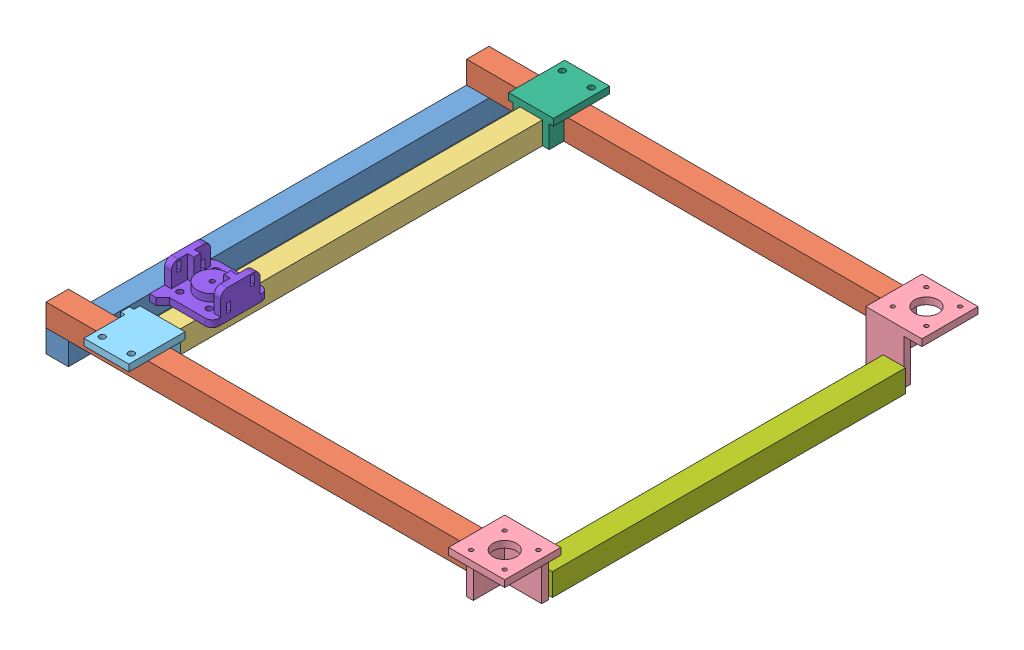
SolidWorks assembly Rails, configuration Domyślna. Lengths in mm.
Overall size (425 66 429).
10 component instances, 8 part files, 28 mates.
Components (placement in the parent):
- Rail_395-1: Rail_395 [Domyślna] at (147.1484 163.3689 533.8319) size (20 20 395)
- Rail_345-1: Rail_345 [Domyślna] at (147.1484 183.3689 513.8319) x (0 0 1) z (-1 0 0) size (20 20 375)
- Rail_345-2: Rail_345 [Domyślna] at (147.1484 183.3689 138.8319) x (0 0 1) z (-1 0 0) size (20 20 375)
- Rail_350-1: Rail_350 [Domyślna] at (207.86 183.3689 511.3319) size (20 20 350)
- Support_moteur-1: Support_moteur [Domyślna] at (572.1484 209.3689 549.8319) x (-1 0 0) z (0 -1 0) size (50 50 46)
- Support_moteur-2: Support_moteur [Domyślna] at (572.1484 209.3689 127.8319) x (0 0 1) z (0 -1 0) size (50 50 46)
- Support_milieu-1: Support_milieu [Domyślna] at (198.06 209.3689 500.8319) x (1 0 0) z (0 -1 0) size (44 50 26)
- Support_milieu_B-1: Support_milieu_B [Domyślna] at (237.66 209.3689 171.8319) x (-1 0 0) z (0 -1 0) size (40 50 26)
- Rail_315-1: Rail_315 [Domyślna] at (541.1484 163.3689 496.3319) size (20 20 315)
- Support_aimant-1: Support_aimant [Domyślna] at (192.86 209.3689 481.256) x (1 0 0) z (0 1 0) size (50 56 26)
Mates (geometry in assembly coordinates):
- Wspólnie1: coincident anti-aligned: plane of Rail_395-1 through (147.1484 183.3689 138.8319) normal (0 1 0); plane of Rail_345-1 through (522.1484 183.3689 513.8319) normal (0 -1 0)
- Wspólnie2: coincident aligned: plane of Rail_395-1 through (147.1484 163.3689 533.8319) normal (0 0 1); plane of Rail_345-1 through (522.1484 183.3689 533.8319) normal (0 0 1)
- Wspólnie3: coincident aligned: plane of Rail_395-1 through (147.1484 163.3689 138.8319) normal (-1 0 0); plane of Rail_345-1 through (147.1484 183.3689 513.8319) normal (-1 0 0)
- Wspólnie4: coincident anti-aligned: plane of Rail_395-1 through (147.1484 183.3689 138.8319) normal (0 1 0); plane of Rail_345-2 through (522.1484 183.3689 138.8319) normal (0 -1 0)
- Wspólnie5: coincident aligned: plane of Rail_395-1 through (147.1484 163.3689 138.8319) normal (0 0 -1); plane of Rail_345-2 through (522.1484 183.3689 138.8319) normal (0 0 -1)
- Wspólnie6: coincident aligned: plane of Rail_395-1 through (147.1484 163.3689 138.8319) normal (-1 0 0); plane of Rail_345-2 through (147.1484 183.3689 138.8319) normal (-1 0 0)
- Wspólnie8: coincident aligned: plane of Rail_345-1 through (522.1484 203.3689 513.8319) normal (0 1 0); plane of Rail_350-1 through (207.86 203.3689 161.3319) normal (0 1 0)
- Odległość1: distance = 2.5 mm anti-aligned: plane of Rail_350-1 through (207.86 183.3689 161.3319) normal (0 0 -1); plane of Rail_345-2 through (522.1484 183.3689 158.8319) normal (0 0 1)
- Wspólnie11: coincident anti-aligned: plane of Rail_345-1 through (522.1484 183.3689 513.8319) normal (1 0 0); plane of Support_moteur-1 through (522.1484 203.3689 549.8319) normal (-1 0 0)
- Wspólnie12: coincident anti-aligned: plane of Rail_345-2 through (522.1484 183.3689 138.8319) normal (1 0 0); plane of Support_moteur-2 through (522.1484 203.3689 127.8319) normal (-1 0 0)
- Równolegle1: parallel aligned: plane of Rail_345-2 through (522.1484 203.3689 138.8319) normal (0 1 0); plane of Support_moteur-2 through (572.1484 209.3689 127.8319) normal (0 1 0)
- Wspólnie14: coincident: plane of Rail_395-1 through (147.1484 163.3689 138.8319) normal (0 -1 0); line of Support_moteur-2 through (522.1484 163.3689 177.8319) axis (0 0 -1)
- Wspólnie15: coincident: plane of Rail_395-1 through (147.1484 163.3689 138.8319) normal (0 -1 0); line of Support_moteur-1 through (522.1484 163.3689 533.8319) axis (0 0 -1)
- Wspólnie16: coincident: plane of Rail_345-1 through (522.1484 183.3689 533.8319) normal (0 0 1); line of Support_moteur-1 through (522.1484 163.3689 533.8319) axis (0 1 0)
- Wspólnie17: coincident aligned: plane of Rail_345-2 through (522.1484 183.3689 138.8319) normal (0 0 -1); plane of Support_moteur-2 through (572.1484 163.3689 138.8319) normal (0 0 -1)
- Wspólnie18: coincident anti-aligned: plane of Rail_350-1 through (207.86 203.3689 161.3319) normal (0 1 0); plane of Support_milieu-1 through (198.06 203.3689 500.8319) normal (0 -1 0)
- Wspólnie19: coincident anti-aligned: plane of Rail_345-1 through (522.1484 183.3689 513.8319) normal (0 0 -1); plane of Support_milieu-1 through (234.26 183.3689 513.8319) normal (0 0 1)
- Wspólnie20: coincident anti-aligned: plane of Rail_350-1 through (207.86 183.3689 161.3319) normal (-1 0 0); plane of Support_milieu-1 through (207.86 183.3689 500.8319) normal (1 0 0)
- Wspólnie21: coincident anti-aligned: plane of Rail_350-1 through (207.86 203.3689 161.3319) normal (0 1 0); plane of Support_milieu_B-1 through (237.66 203.3689 171.8319) normal (0 -1 0)
- Wspólnie23: coincident anti-aligned: plane of Rail_345-2 through (522.1484 183.3689 158.8319) normal (0 0 1); plane of Support_milieu_B-1 through (233.86 183.3689 158.8319) normal (0 0 -1)
- Wspólnie24: coincident anti-aligned: plane of Rail_350-1 through (227.86 183.3689 161.3319) normal (1 0 0); plane of Support_milieu_B-1 through (227.86 183.3689 171.8319) normal (-1 0 0)
- Wspólnie29: coincident: line of Support_moteur-1 through (561.1484 163.3689 499.8319) axis (0 1 0); plane of Rail_315-1 through (561.1484 163.3689 181.3319) normal (1 0 0)
- Wspólnie30: coincident: line of Support_moteur-1 through (522.1484 163.3689 499.8319) axis (1 0 0); plane of Rail_315-1 through (541.1484 163.3689 181.3319) normal (0 -1 0)
- Wspólnie31: coincident aligned: plane of Support_moteur-1 through (561.1484 163.3689 549.8319) normal (1 0 0); plane of Rail_315-1 through (561.1484 163.3689 181.3319) normal (1 0 0)
- Wspólnie32: coincident aligned: plane of Support_moteur-1 through (572.1484 163.3689 549.8319) normal (0 -1 0); plane of Rail_315-1 through (541.1484 163.3689 181.3319) normal (0 -1 0)
- Wspólnie34: coincident anti-aligned: plane of Rail_350-1 through (207.86 203.3689 161.3319) normal (0 1 0); plane of Support_aimant-1 through (192.86 203.3689 481.256) normal (0 -1 0)
- Odległość2: distance = 15 mm aligned: plane of Support_aimant-1 through (192.86 203.3689 481.256) normal (-1 0 0); plane of Rail_350-1 through (207.86 183.3689 161.3319) normal (-1 0 0)
- Odległość3: distance = 3.5 mm anti-aligned: plane of Rail_315-1 through (541.1484 163.3689 181.3319) normal (0 0 -1); plane of Support_moteur-2 through (572.1484 203.3689 177.8319) normal (0 0 1)
